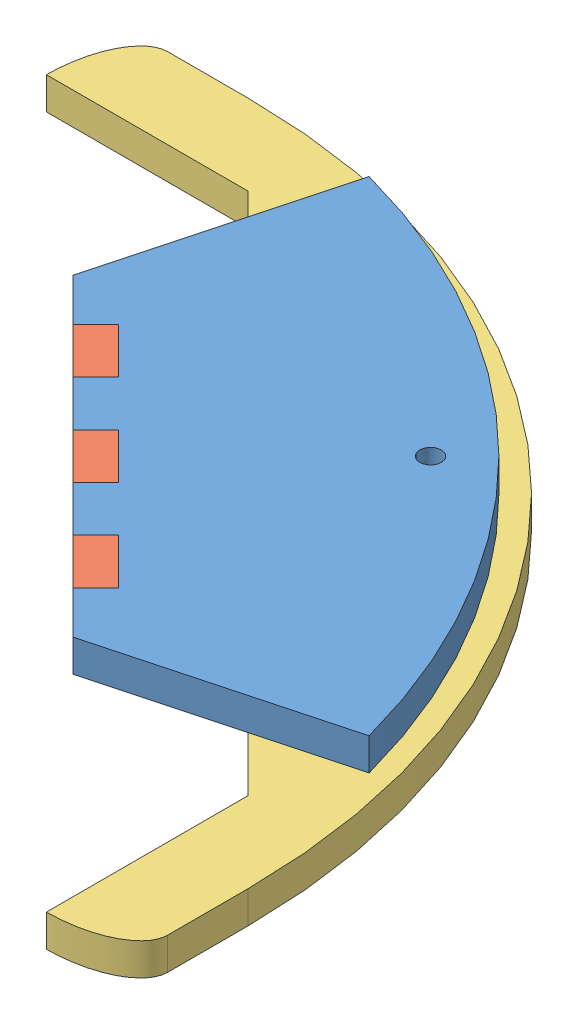
SolidWorks assembly bumper_total, configuration MirrorDefault. Lengths in mm.
Overall size (127.1 15.24 127.1).
3 component instances, 3 part files, 6 mates.
Components (placement in the parent):
- bumper_top-1: bumper_top [MirrorDefault] at (-52.8514 69.6772 58.426) size (86.19 5.08 86.19)
- bumper_flange-1: bumper_flange [MirrorDefault] at (-24.4456 59.5172 -5.9008) x (0.707107 0 0.707107) z (-0.707107 0 0.707107) size (50.8 15.24 5.08)
- bumper-2: bumper [Default] at (-62.9783 64.5972 68.5529)
Mates (geometry in assembly coordinates):
- Width1: width: plane of bumper_top-1 through (-52.8514 74.7572 58.426) normal (-0.965926 0 -0.258819); plane of bumper_top-1 through (-52.8514 74.7572 58.426) normal (0.258819 0 0.965926); plane of bumper_flange-1 through (-28.0377 59.5172 -2.3087) normal (-0.707107 0 -0.707107); plane of bumper_flange-1 through (7.8833 59.5172 33.6123) normal (0.707107 0 0.707107)
- Coincident2: coincident: plane of bumper_top-1 through (-10.0772 74.7572 15.6518) normal (-0.707107 0 0.707107); plane of bumper_flange-1 through (-28.0377 59.5172 -2.3087) normal (-0.707107 0 0.707107)
- Coincident3: coincident: plane of bumper_top-1 through (-52.8514 74.7572 58.426) normal (0 1 0); plane of bumper_flange-1 through (-28.0377 74.7572 -2.3087) normal (0 1 0)
- Coincident4: coincident: plane of bumper_top-1 through (-52.8514 69.6772 58.426) normal (0 -1 0); plane of bumper-2 through (-50.2783 69.6772 55.8529) normal (0 1 0)
- Concentric2: concentric: cylinder of bumper_top-1 through (18.0926 74.7572 -12.518) axis (0 1 0) radius 1.7; cylinder of bumper-2 through (18.0926 69.6772 -12.518) axis (0 -1 0) radius 1.8
- Width2: width: plane of bumper_top-1 through (-52.8514 74.7572 58.426) normal (-0.965926 0 -0.258819); plane of bumper_top-1 through (-52.8514 74.7572 58.426) normal (0.258819 0 0.965926); plane of bumper-2 through (57.6717 69.6772 68.5529) normal (1 0 0); plane of bumper-2 through (-62.9783 69.6772 -52.0971) normal (0 0 -1)
